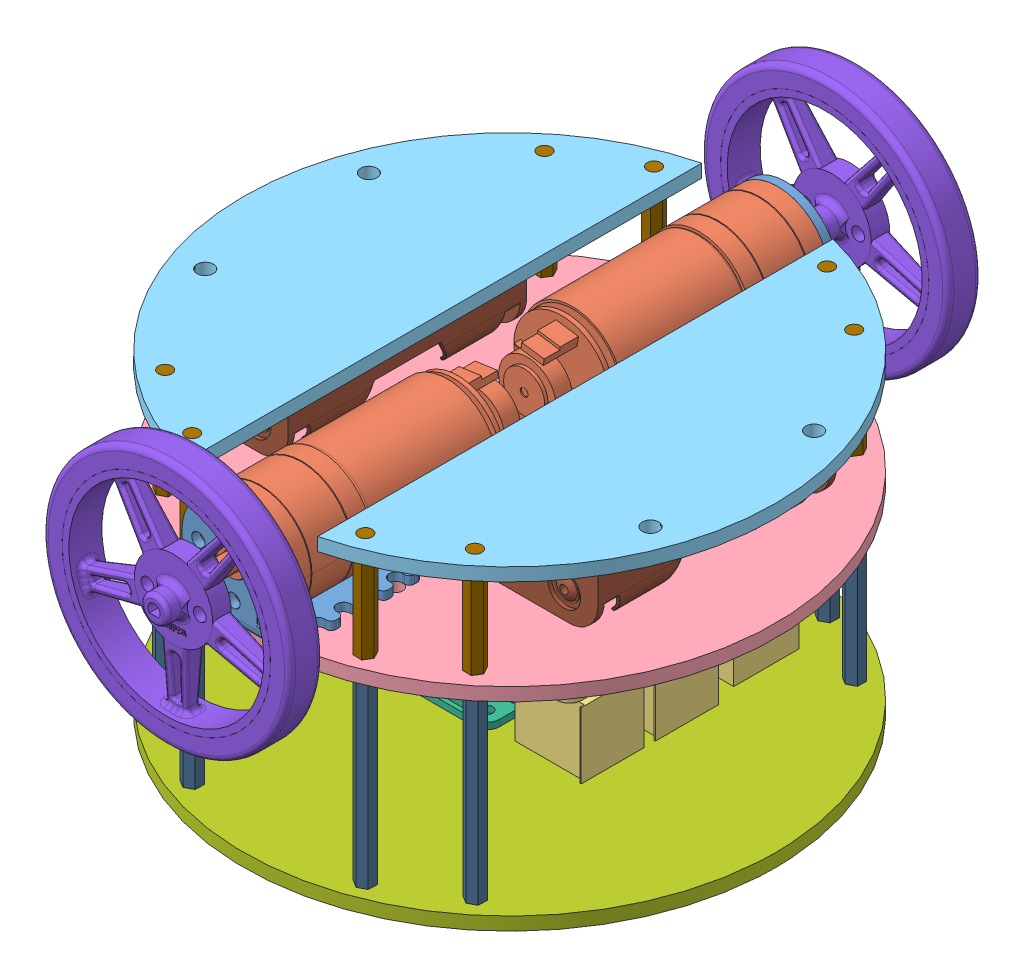
SolidWorks assembly Fleet v1.0, configuration Default. Lengths in mm.
Overall size (129 95.35 170.77).
30 component instances, 11 part files, 66 mates.
Components (placement in the parent):
- pololu-25d-mm-metal-gearmotor-bracket-1: pololu-25d-mm-metal-gearmotor-bracket [Default] at (11.9651 32.2947 52.3664) size (25 27 52)
- 25d-metal-gearmotor-20.4-encoder.step-1: 25d-metal-gearmotor-20.4-encoder.step [Default] at (41.8401 33.2947 46.4914) x (-1 0 0) z (0 0 1) size (25 32.85 74)
- 25d-metal-gearmotor-20.4-encoder.step-2: 25d-metal-gearmotor-20.4-encoder.step [Default] at (-19.9099 33.2947 -46.7586) x (1 0 0) z (0 0 -1) size (25 32.85 74)
- pololu-25d-mm-metal-gearmotor-bracket-2: pololu-25d-mm-metal-gearmotor-bracket [Default] at (9.9651 32.2947 -52.6336) x (-1 0 0) z (0 0 -1) size (25 27 52)
- Rpi3Bplus-1: Rpi3Bplus [Default] at (-31.5349 5.5943 -28.1336) x (1 0 0) z (0 0 -1) size (87.03 17.52 58.47)
- Main Plate 1-1: Main Plate 1 [Default] at (26.1337 18.7947 0.2329) x (1 0 0) z (0 -1 0) size (129 129 3.17)
- SubPlate 1-1: SubPlate 1 [Default] at (26.8901 43.9697 0.2329) x (1 0 0) z (0 -1 0) size (48.58 125.01 3.17)
- SubPlate 1-2: SubPlate 1 [Default] at (-4.9599 43.9697 -0.5) x (-1 0 0) z (0 -1 0) size (48.58 125.01 3.17)
- dual-tb9051ftg-motor-driver-raspberry-pi.step-1: dual-tb9051ftg-motor-driver-raspberry-pi.step [Default] at (-31.5349 -9.9043 -28.1336) x (1 0 0) z (0 -1 0) size (65 56 20.07)
- Top Plate-1: Top Plate [Default] at (25.9074 -29.3803 -5.7671) x (1 0 0) z (0 -1 0) size (129 129 3.17)
- pololu-wheel-60x8mm-black-1: pololu-wheel-60x8mm-black [Default] at (11.4421 32.7947 79.6164) x (0 0 -1) z (-1 0 0) size (11 60 60)
- pololu-wheel-60x8mm-black-2: pololu-wheel-60x8mm-black [Default] at (11.3417 32.7947 -80.154) x (0 0 -1) z (-1 0 0) size (11 60 60)
- 22mm Standoff-1: 22mm Standoff [Default] at (31.9651 18.7947 55.8664) size (4.39 28.35 3.87)
- 22mm Standoff-2: 22mm Standoff [Default] at (-26.5984 18.7947 -46.1336) size (4.39 28.35 3.87)
- 22mm Standoff-3: 22mm Standoff [Default] at (-10.0349 18.7947 -56.1336) size (4.39 28.35 3.87)
- 22mm Standoff-4: 22mm Standoff [Default] at (48.5286 18.7947 -46.1336) size (4.39 28.35 3.87)
- 22mm Standoff-5: 22mm Standoff [Default] at (48.5286 18.7947 45.8664) size (4.39 28.35 3.87)
- 22mm Standoff-6: 22mm Standoff [Default] at (31.9651 18.7947 -56.1336) size (4.39 28.35 3.87)
- 22mm Standoff-7: 22mm Standoff [Default] at (-10.0349 18.7947 55.8664) size (4.39 28.35 3.87)
- 22mm Standoff-8: 22mm Standoff [Default] at (-26.5984 40.7947 45.8664) x (0.837169 0 0.546944) z (0.546944 0 -0.837169) size (4.39 28.35 3.87)
- 45mm Standoff-1: 45mm Standoff [Default] at (-10.0349 15.6197 55.8664) x (-0.837169 0 -0.546944) z (-0.546944 0 0.837169) size (4.39 48.18 3.83)
- 45mm Standoff-2: 45mm Standoff [Default] at (31.9651 15.6197 55.8664) x (0.837169 0 0.546944) z (0.546944 0 -0.837169) size (4.39 48.18 3.83)
- 45mm Standoff-3: 45mm Standoff [Default] at (-10.0349 15.6197 -56.1336) x (-0.837169 0 -0.546944) z (-0.546944 0 0.837169) size (4.39 48.18 3.83)
- 45mm Standoff-4: 45mm Standoff [Default] at (-26.6691 15.6197 -46.1336) x (-0.837169 0 -0.546944) z (-0.546944 0 0.837169) size (4.39 48.18 3.83)
- 45mm Standoff-6: 45mm Standoff [Default] at (48.5993 15.6197 -46.1336) x (-0.837169 0 -0.546944) z (-0.546944 0 0.837169) size (4.39 48.18 3.83)
- 45mm Standoff-7: 45mm Standoff [Default] at (31.9651 15.6197 -56.1336) x (-0.837169 0 -0.546944) z (-0.546944 0 0.837169) size (4.39 48.18 3.83)
- 45mm Standoff-8: 45mm Standoff [Default] at (48.5993 15.6197 45.8664) x (-0.837169 0 -0.546944) z (-0.546944 0 0.837169) size (4.39 48.18 3.83)
- 45mm Standoff-9: 45mm Standoff [Default] at (-26.6691 15.6197 45.8664) x (0.837169 0 0.546944) z (0.546944 0 -0.837169) size (4.39 48.18 3.83)
- AABattery Holder.stp-1: AABattery Holder.stp [Default] at (64.3901 33.2447 -35.3624) x (1 0 0) z (0 -1 0) size (34.4 57.98 19)
- AABattery Holder.stp-2: AABattery Holder.stp [Default] at (-8.9599 33.2447 -33.6011) x (1 0 0) z (0 -1 0) size (34.4 57.98 19)
Mates (geometry in assembly coordinates):
- Concentric1: concentric: circle of pololu-25d-mm-metal-gearmotor-bracket-1; circle of 25d-metal-gearmotor-20.4-encoder.step-1
- Concentric2: concentric: circle of pololu-25d-mm-metal-gearmotor-bracket-1; circle of 25d-metal-gearmotor-20.4-encoder.step-1
- Coincident1: coincident: plane of pololu-25d-mm-metal-gearmotor-bracket-1 through (23.4651 20.7947 64.8664) normal (0 0 -1); plane of 25d-metal-gearmotor-20.4-encoder.step-1 through (10.9651 33.2947 64.8664) normal (0 0 1)
- Concentric3: concentric: circle of 25d-metal-gearmotor-20.4-encoder.step-2; circle of pololu-25d-mm-metal-gearmotor-bracket-2
- Concentric4: concentric: circle of 25d-metal-gearmotor-20.4-encoder.step-2; circle of pololu-25d-mm-metal-gearmotor-bracket-2
- Coincident2: coincident: plane of 25d-metal-gearmotor-20.4-encoder.step-2 through (10.9651 33.2947 -65.1336) normal (0 0 -1); plane of pololu-25d-mm-metal-gearmotor-bracket-2 through (-1.5349 20.7947 -65.1336) normal (0 0 1)
- Coincident3: coincident: plane of pololu-25d-mm-metal-gearmotor-bracket-1 through (23.4651 18.7947 64.8664) normal (0 -1 0); plane of pololu-25d-mm-metal-gearmotor-bracket-2 through (-1.5349 18.7947 -65.1336) normal (0 -1 0)
- Coincident5: coincident: plane of pololu-25d-mm-metal-gearmotor-bracket-1 through (-1.5349 21.4297 64.2314) normal (-1 0 0); plane of pololu-25d-mm-metal-gearmotor-bracket-2 through (-1.5349 21.4297 -67.1336) normal (-1 0 0)
- Coincident12: coincident: circle of pololu-25d-mm-metal-gearmotor-bracket-2; circle of Main Plate 1-1
- Coincident13: coincident: cylinder of pololu-25d-mm-metal-gearmotor-bracket-1 through (10.9651 18.7947 60.5164) axis (0 1 0) radius 1.65; circle of Main Plate 1-1
- Concentric11: concentric: cylinder of Rpi3Bplus-1 through (-28.0349 4.1211 -24.6336) axis (0 1 0) radius 1.375; cylinder of Main Plate 1-1 through (-28.0349 15.6197 -24.6336) axis (0 1 0) radius 1.4
- Concentric12: concentric: cylinder of Rpi3Bplus-1 through (-28.0349 4.1211 24.3664) axis (0 1 0) radius 1.375; cylinder of Main Plate 1-1 through (-28.0349 15.6197 24.3664) axis (0 1 0) radius 1.4
- Distance6: distance = 10 mm: plane of Rpi3Bplus-1 through (50.4651 5.6197 -25.1336) normal (0 1 0); plane of Main Plate 1-1 through (10.9651 15.6197 -0.1336) normal (0 -1 0)
- Concentric13: concentric: circle of Main Plate 1-1; circle of SubPlate 1-1
- Concentric14: concentric: circle of Main Plate 1-1; circle of SubPlate 1-1
- Distance7: distance = 22 mm: plane of SubPlate 1-1 through (10.9651 40.7947 -0.1336) normal (0 -1 0); plane of Main Plate 1-1 through (10.9651 18.7947 -0.1336) normal (0 1 0)
- Concentric15: concentric: circle of Main Plate 1-1; circle of SubPlate 1-2
- Concentric16: concentric: circle of Main Plate 1-1; circle of SubPlate 1-2
- Distance8: distance = 22 mm: plane of SubPlate 1-2 through (10.9651 40.7947 -0.1336) normal (0 -1 0); plane of Main Plate 1-1 through (10.9651 18.7947 -0.1336) normal (0 1 0)
- Distance9: distance = 14 mm: plane of Rpi3Bplus-1 through (-28.5349 4.0957 24.8664) normal (0 -1 0); plane of dual-tb9051ftg-motor-driver-raspberry-pi.step-1 through (-28.5349 -9.9043 -25.1336) normal (0 1 0)
- Coincident28: coincident: plane of Rpi3Bplus-1 through (-28.5349 4.1211 27.8664) normal (0 0 1); plane of dual-tb9051ftg-motor-driver-raspberry-pi.step-1 through (-28.5349 -11.4791 27.8664) normal (0 0 1)
- Coincident29: coincident: plane of Rpi3Bplus-1 through (-31.5349 4.1211 -25.1336) normal (-1 0 0); plane of dual-tb9051ftg-motor-driver-raspberry-pi.step-1 through (-31.5349 -11.4791 9.3664) normal (-1 0 0)
- Concentric17: concentric: circle of Main Plate 1-1; circle of Top Plate-1
- Concentric18: concentric: cylinder of Main Plate 1-1 through (31.9651 15.6197 55.8664) axis (0 1 0) radius 1.65; circle of Top Plate-1
- Distance10: distance = 45 mm: plane of Top Plate-1 through (10.9651 -29.3803 -0.1336) normal (0 1 0); plane of Main Plate 1-1 through (10.9651 15.6197 -0.1336) normal (0 -1 0)
- Coincident34: coincident: plane of 25d-metal-gearmotor-20.4-encoder.step-1 through (10.9651 31.7947 69.3664) normal (0 -1 0); plane of pololu-wheel-60x8mm-black-1 through (12.5601 31.7947 75.6164) normal (0 1 0)
- Parallel8: parallel: cylinder of 25d-metal-gearmotor-20.4-encoder.step-1 through (10.9651 33.2947 64.8664) axis (0 0 1) radius 2; cylinder of pololu-wheel-60x8mm-black-1 through (11.4421 32.7947 75.6164) axis (0 0 1) radius 1.5
- Coincident38: coincident: plane of 25d-metal-gearmotor-20.4-encoder.step-2 through (10.9651 31.7947 -69.6336) normal (0 -1 0); plane of pololu-wheel-60x8mm-black-2 through (12.4598 31.7947 -84.154) normal (0 1 0)
- Parallel9: parallel: cylinder of 25d-metal-gearmotor-20.4-encoder.step-2 through (10.9651 33.2947 -65.1336) axis (0 0 -1) radius 2; cylinder of pololu-wheel-60x8mm-black-2 through (11.3417 32.7947 -84.154) axis (0 0 1) radius 1.5
- Concentric27: concentric: cylinder of Main Plate 1-1 through (31.9651 15.6197 55.8664) axis (0 1 0) radius 1.65; cylinder of 22mm Standoff-1 through (31.9651 15.6197 55.8664) axis (0 1 0) radius 1.65
- Concentric28: concentric: circle of SubPlate 1-1; cylinder of 22mm Standoff-1 through (31.9651 43.9697 55.8664) axis (0 -1 0) radius 1.65
- Coincident40: coincident: plane of SubPlate 1-1 through (10.9651 40.7947 -0.1336) normal (0 -1 0); plane of 22mm Standoff-1 through (31.9651 40.7947 55.8664) normal (0 1 0)
- Concentric29: concentric: cylinder of Main Plate 1-1 through (48.5286 15.6197 45.8664) axis (0 1 0) radius 1.65; cylinder of 22mm Standoff-5 through (48.5286 15.6197 45.8664) axis (0 1 0) radius 1.65
- Coincident41: coincident: plane of Main Plate 1-1 through (10.9651 18.7947 -0.1336) normal (0 1 0); plane of 22mm Standoff-5 through (48.5286 18.7947 45.8664) normal (0 -1 0)
- Concentric30: concentric: cylinder of Main Plate 1-1 through (48.5286 15.6197 -46.1336) axis (0 1 0) radius 1.65; cylinder of 22mm Standoff-4 through (48.5286 15.6197 -46.1336) axis (0 1 0) radius 1.65
- Coincident42: coincident: plane of Main Plate 1-1 through (10.9651 18.7947 -0.1336) normal (0 1 0); plane of 22mm Standoff-4 through (48.5286 18.7947 -46.1336) normal (0 -1 0)
- Concentric31: concentric: cylinder of Main Plate 1-1 through (31.9651 15.6197 -56.1336) axis (0 1 0) radius 1.65; cylinder of 22mm Standoff-6 through (31.9651 15.6197 -56.1336) axis (0 1 0) radius 1.65
- Coincident43: coincident: plane of Main Plate 1-1 through (10.9651 18.7947 -0.1336) normal (0 1 0); plane of 22mm Standoff-6 through (31.9651 18.7947 -56.1336) normal (0 -1 0)
- Concentric32: concentric: cylinder of Main Plate 1-1 through (-10.0349 15.6197 -56.1336) axis (0 1 0) radius 1.65; cylinder of 22mm Standoff-3 through (-10.0349 15.6197 -56.1336) axis (0 1 0) radius 1.65
- Coincident44: coincident: plane of Main Plate 1-1 through (10.9651 18.7947 -0.1336) normal (0 1 0); plane of 22mm Standoff-3 through (-10.0349 18.7947 -56.1336) normal (0 -1 0)
- Concentric33: concentric: cylinder of Main Plate 1-1 through (-26.5984 15.6197 -46.1336) axis (0 1 0) radius 1.65; cylinder of 22mm Standoff-2 through (-26.5984 15.6197 -46.1336) axis (0 1 0) radius 1.65
- Coincident45: coincident: plane of Main Plate 1-1 through (10.9651 18.7947 -0.1336) normal (0 1 0); plane of 22mm Standoff-2 through (-26.5984 18.7947 -46.1336) normal (0 -1 0)
- Concentric34: concentric: cylinder of Main Plate 1-1 through (-26.5984 15.6197 45.8664) axis (0 1 0) radius 1.65; cylinder of 22mm Standoff-8 through (-26.5984 43.9697 45.8664) axis (0 -1 0) radius 1.65
- Coincident46: coincident: plane of Main Plate 1-1 through (10.9651 18.7947 -0.1336) normal (0 1 0); plane of 22mm Standoff-8 through (-26.5984 18.7947 45.8664) normal (0 -1 0)
- Concentric35: concentric: cylinder of Main Plate 1-1 through (-10.0349 15.6197 55.8664) axis (0 1 0) radius 1.65; cylinder of 22mm Standoff-7 through (-10.0349 15.6197 55.8664) axis (0 1 0) radius 1.65
- Coincident47: coincident: plane of Main Plate 1-1 through (10.9651 18.7947 -0.1336) normal (0 1 0); plane of 22mm Standoff-7 through (-10.0349 18.7947 55.8664) normal (0 -1 0)
- Concentric36: concentric: cylinder of Top Plate-1 through (-26.6691 -32.5553 45.8664) axis (0 1 0) radius 1.65; cylinder of 45mm Standoff-9 through (-26.6691 -32.5553 45.8664) axis (0 1 0) radius 1.65
- Coincident48: coincident: plane of Main Plate 1-1 through (10.9651 15.6197 -0.1336) normal (0 -1 0); plane of 45mm Standoff-9 through (-26.6691 15.6197 45.8664) normal (0 1 0)
- Coincident49: coincident: plane of Main Plate 1-1 through (10.9651 15.6197 -0.1336) normal (0 -1 0); plane of 45mm Standoff-1 through (-10.0349 15.6197 55.8664) normal (0 1 0)
- Concentric37: concentric: cylinder of Top Plate-1 through (-10.0349 -32.5553 55.8664) axis (0 1 0) radius 1.65; cylinder of 45mm Standoff-1 through (-10.0349 -32.5553 55.8664) axis (0 1 0) radius 1.65
- Coincident50: coincident: plane of Main Plate 1-1 through (10.9651 15.6197 -0.1336) normal (0 -1 0); plane of 45mm Standoff-2 through (31.9651 15.6197 55.8664) normal (0 1 0)
- Concentric38: concentric: cylinder of Top Plate-1 through (31.9651 -32.5553 55.8664) axis (0 1 0) radius 1.65; cylinder of 45mm Standoff-2 through (31.9651 -32.5553 55.8664) axis (0 1 0) radius 1.65
- Coincident51: coincident: plane of Main Plate 1-1 through (10.9651 15.6197 -0.1336) normal (0 -1 0); plane of 45mm Standoff-8 through (48.5993 15.6197 45.8664) normal (0 1 0)
- Concentric39: concentric: cylinder of Top Plate-1 through (48.5993 -32.5553 45.8664) axis (0 1 0) radius 1.65; cylinder of 45mm Standoff-8 through (48.5993 -32.5553 45.8664) axis (0 1 0) radius 1.65
- Coincident52: coincident: plane of Main Plate 1-1 through (10.9651 15.6197 -0.1336) normal (0 -1 0); plane of 45mm Standoff-6 through (48.5993 15.6197 -46.1336) normal (0 1 0)
- Concentric40: concentric: cylinder of Top Plate-1 through (48.5993 -32.5553 -46.1336) axis (0 1 0) radius 1.65; cylinder of 45mm Standoff-6 through (48.5993 -32.5553 -46.1336) axis (0 1 0) radius 1.65
- Coincident53: coincident: plane of Main Plate 1-1 through (10.9651 15.6197 -0.1336) normal (0 -1 0); plane of 45mm Standoff-7 through (31.9651 15.6197 -56.1336) normal (0 1 0)
- Concentric41: concentric: cylinder of Top Plate-1 through (31.9651 -32.5553 -56.1336) axis (0 1 0) radius 1.65; cylinder of 45mm Standoff-7 through (31.9651 -32.5553 -56.1336) axis (0 1 0) radius 1.65
- Coincident54: coincident: plane of Main Plate 1-1 through (10.9651 15.6197 -0.1336) normal (0 -1 0); plane of 45mm Standoff-3 through (-10.0349 15.6197 -56.1336) normal (0 1 0)
- Concentric42: concentric: cylinder of Top Plate-1 through (-10.0349 -32.5553 -56.1336) axis (0 1 0) radius 1.65; cylinder of 45mm Standoff-3 through (-10.0349 -32.5553 -56.1336) axis (0 1 0) radius 1.65
- Coincident55: coincident: plane of Main Plate 1-1 through (10.9651 15.6197 -0.1336) normal (0 -1 0); plane of 45mm Standoff-4 through (-26.6691 15.6197 -46.1336) normal (0 1 0)
- Concentric43: concentric: cylinder of Top Plate-1 through (-26.6691 -32.5553 -46.1336) axis (0 1 0) radius 1.65; cylinder of 45mm Standoff-4 through (-26.6691 -32.5553 -46.1336) axis (0 1 0) radius 1.65
- Coincident56: coincident: plane of SubPlate 1-1 through (10.9651 40.7947 -0.1336) normal (0 -1 0); plane of AABattery Holder.stp-1 through (62.1401 40.7947 29.3876) normal (0 1 0)
- Distance11: distance = 5 mm: plane of AABattery Holder.stp-1 through (31.8901 39.7947 -24.6124) normal (-1 0 0); plane of SubPlate 1-1 through (26.8901 40.7947 62.3696) normal (-1 0 0)
- Coincident58: coincident: plane of SubPlate 1-2 through (10.9651 40.7947 -0.1336) normal (0 -1 0); plane of AABattery Holder.stp-2 through (-11.2099 40.7947 31.1489) normal (0 1 0)
- Distance12: distance = 5 mm: plane of AABattery Holder.stp-2 through (-9.9599 39.7947 -22.8511) normal (1 0 0); plane of SubPlate 1-2 through (-4.9599 40.7947 -62.6367) normal (1 0 0)
